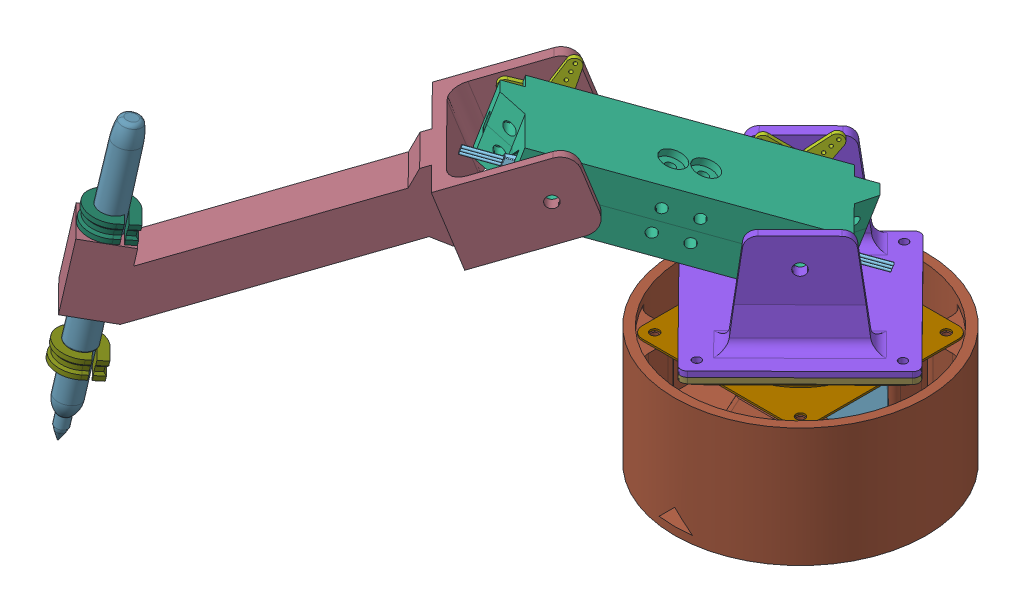
SolidWorks assembly FullArm, configuration Default. Lengths in mm.
Overall size (280.36 181.44 270.92).
49 component instances, 18 part files, 6 mates.
Components (placement in the parent):
- J2-1: J2 [Default] at (0 57.04 9.85) x (0.703043 0 0.711147) z (-0.711147 0 0.703043) size (77.5 78.25 149.97) (flexible)
  - Servo-1: Servo [Default] at (-12.46 52.3124 91.7081) x (0 0.949712 -0.313125) z (-1 0 0) size (20.01 68.31 42.11)
    - Parallax-900-00005-08-25-Servo-CR-HSCR-STD.stp-1: Parallax-900-00005-08-25-Servo-CR-HSCR-STD.stp [Default] at origin size (21 68.31 45.51)
      - SCREW-1.7x24.stp-1: SCREW-1.7x24.stp [Default] at (0 0 -2.6) size (18 38.5 24.9)
        - b4.stp-1: b4.stp [Default] at (12.4 -16.06 -0.6) size (3 3 24.9)
        - b3.stp-1: b3.stp [Default] at (-2.6 -16.06 -0.6) size (3 3 24.9)
        - b2.stp-1: b2.stp [Default] at (-2.6 19.44 -0.6) size (3 3 24.9)
        - b1.stp-1: b1.stp [Default] at (12.4 19.44 -0.6) size (3 3 24.9)
      - HORN-D.stp-1: HORN-D.stp [Default] at (-22.975 33.5463 -1.6) x (1 0 0) z (0 -1 0) size (21 6.2 21) (hidden)
      - Screw_3x8.stp-1: Screw_3x8.stp [Default] at (62.7475 7.2555 -24.6) x (-0.749146 0.662405 0) z (0 0 1) size (5.6 5.6 10.4) (hidden)
      - Case.stp-1: Case.stp [Default] at origin size (20.01 68.31 42.11)
  - Joint2Channel-1: Joint2Channel [Default] at (12.65 30.2513 10.7445) x (0 0.313125 0.949712) z (0 -0.949712 0.313125) size (127.08 40 21.04)
  - Servo-2: Servo [Default] at (-12.46 38.677 -12.882) x (0 -0.949712 0.313125) z (-1 0 0) size (20.01 68.31 42.11)
    - Parallax-900-00005-08-25-Servo-CR-HSCR-STD.stp-1: Parallax-900-00005-08-25-Servo-CR-HSCR-STD.stp [Default] at origin size (21 68.31 45.51)
      - SCREW-1.7x24.stp-1: SCREW-1.7x24.stp [Default] at (0 0 -2.6) size (18 38.5 24.9)
        - b4.stp-1: b4.stp [Default] at (12.4 -16.06 -0.6) size (3 3 24.9)
        - b3.stp-1: b3.stp [Default] at (-2.6 -16.06 -0.6) size (3 3 24.9)
        - b2.stp-1: b2.stp [Default] at (-2.6 19.44 -0.6) size (3 3 24.9)
        - b1.stp-1: b1.stp [Default] at (12.4 19.44 -0.6) size (3 3 24.9)
      - HORN-D.stp-1: HORN-D.stp [Default] at (-22.975 33.5463 -1.6) x (1 0 0) z (0 -1 0) size (21 6.2 21) (hidden)
      - Screw_3x8.stp-1: Screw_3x8.stp [Default] at (62.7475 7.2555 -24.6) x (-0.749146 0.662405 0) z (0 0 1) size (5.6 5.6 10.4) (hidden)
      - Case.stp-1: Case.stp [Default] at origin size (20.01 68.31 42.11)
  - Joint2Channel-2: Joint2Channel [Default] at (12.65 60.7381 68.0816) x (0 -0.313125 -0.949712) z (0 0.949712 -0.313125) size (127.08 40 21.04)
  - futaba_horn_type_A-1: futaba_horn_type_A [Default] at (-30.5 67.0795 79.0888) x (0 0.356857 -0.934159) z (0 -0.934159 -0.356857) size (29.15 5.85 29.15)
  - futaba_horn_type_A-2: futaba_horn_type_A [Default] at (-30.5 24.3107 2.6065) x (0 -0.026181 0.999657) z (0 0.999657 0.026181) size (29.15 5.85 29.15)
  - Joint2Base-1: Joint2Base [Default] at origin size (77.5 45.5 77.5)
- J1-1: J1 [Default] at origin size (113 60.54 113) (flexible)
  - ThrustBearing-2: ThrustBearing [Default] at (116.9051 36.0777 -43.3725) size (106.89 8 106.89) (flexible)
    - BearingPart-1: BearingPart [Default] at (-116.9051 10.4623 53.2225) size (76.2 4 76.2)
    - BearingPart-2: BearingPart [Default] at (-116.9051 18.4623 53.2225) x (0.711147 0 -0.703043) z (-0.703043 0 -0.711147) size (76.2 4 76.2)
  - MotorAttachment-1: MotorAttachment [Default] at (0 43.54 9.85) x (0.005731 0 -0.999984) z (0.999984 0 0.005731) size (32 6 32)
  - Servo-2: Servo [Default] at (-9.9 25.5 20.15) x (1 0 0) z (0 1 0) size (20.01 68.31 42.11)
    - Parallax-900-00005-08-25-Servo-CR-HSCR-STD.stp-1: Parallax-900-00005-08-25-Servo-CR-HSCR-STD.stp [Default] at origin size (21 68.31 45.51)
      - SCREW-1.7x24.stp-1: SCREW-1.7x24.stp [Default] at (0 0 -2.6) size (18 38.5 24.9)
        - b4.stp-1: b4.stp [Default] at (12.4 -16.06 -0.6) size (3 3 24.9)
        - b3.stp-1: b3.stp [Default] at (-2.6 -16.06 -0.6) size (3 3 24.9)
        - b2.stp-1: b2.stp [Default] at (-2.6 19.44 -0.6) size (3 3 24.9)
        - b1.stp-1: b1.stp [Default] at (12.4 19.44 -0.6) size (3 3 24.9)
      - HORN-D.stp-1: HORN-D.stp [Default] at (-22.975 33.5463 -1.6) x (1 0 0) z (0 -1 0) size (21 6.2 21) (hidden)
      - Screw_3x8.stp-1: Screw_3x8.stp [Default] at (62.7475 7.2555 -24.6) x (-0.749146 0.662405 0) z (0 0 1) size (5.6 5.6 10.4) (hidden)
      - Case.stp-1: Case.stp [Default] at origin size (20.01 68.31 42.11)
  - Base-1: Base [Default] at origin size (113 53.5 113)
  - futaba_horn_type_A-1: futaba_horn_type_A [Default] at (8.5932 43.54 9.7237) x (0.314215 0 -0.949352) z (-0.949352 0 -0.314215) size (29.15 5.85 29.15)
  - Interface-1: Interface [Default] at (0 57.04 9.85) x (0.711147 0 -0.703043) z (-0.703043 0 -0.711147) size (77.5 7.5 77.5)
- J3-1: J3 [Default] at (-77.856 104.7304 86.8188) x (0.703043 0 0.711147) z (-0.236298 0.943182 0.233606) size (60.8 203.5 117.62) (flexible)
  - Joint 3-1: Joint 3 [Default] at origin size (60.8 179.32 41.98)
  - Sharpie Marker-1: Sharpie Marker [Default] at (0 -88.7103 58.1333) x (0.991149 0.114968 -0.066377) z (-0.132754 0.85836 -0.495575) size (12.29 127.84 12.29)
  - SharpieClampLarge-1: SharpieClampLarge [Default] at (0 -110.1603 20.9808) x (1 0 0) z (0 -0.866025 0.5) size (19.8 8 19.8)
  - SharpieClampSmall-1: SharpieClampSmall [Default] at (0 -137.1603 -25.7846) x (1 0 0) z (0 -0.866025 0.5) size (19.2 8 19.2)
Mates (geometry in assembly coordinates):
- Concentric1: concentric anti-aligned: cylinder of J2-1/Joint2Base-1 through (-0.2654 59.54 56.1647) axis (0 -1 0) radius 1.83; cylinder of J1-1/Interface-1 through (-0.2654 54.54 56.1647) axis (0 1 0) radius 1.83
- Concentric2: concentric anti-aligned: cylinder of J2-1/Joint2Base-1 through (46.3147 59.54 10.1154) axis (0 -1 0) radius 1.83; cylinder of J1-1/Interface-1 through (46.3147 54.54 10.1154) axis (0 1 0) radius 1.83
- Coincident1: coincident: plane of J2-1/Joint2Base-1 through (0 57.04 9.85) normal (0 -1 0); line of J1-1/Interface-1 through (-2.4232 57.04 62.5164) axis (-0.703043 0 -0.711147)
- Concentric3: concentric anti-aligned: cylinder of J2-1/futaba_horn_type_A-1 through (-73.9846 115.5294 47.1339) axis (-0.703043 0 -0.711147) radius 1.5; cylinder of J3-1/Joint 3-1 through (-45.4059 115.5294 76.042) axis (0.703043 0 0.711147) radius 2.65
- Coincident2: coincident anti-aligned: plane of J2-1/futaba_horn_type_A-1 through (-79.6662 123.504 45.7199) normal (-0.703043 0 -0.711147); plane of J3-1/Joint 3-1 through (-64.9994 104.7581 31.2202) normal (0.703043 0 0.711147)
- Angle1: planar angle = 2.52523 rad aligned: plane of J2-1/futaba_horn_type_A-1 through (-86.352 125.0222 55.1418) normal (0.19492 0.961703 -0.192699); plane of J3-1/Joint 3-1 through (-28.4411 104.7581 68.1998) normal (0.236298 -0.943182 -0.233606)
